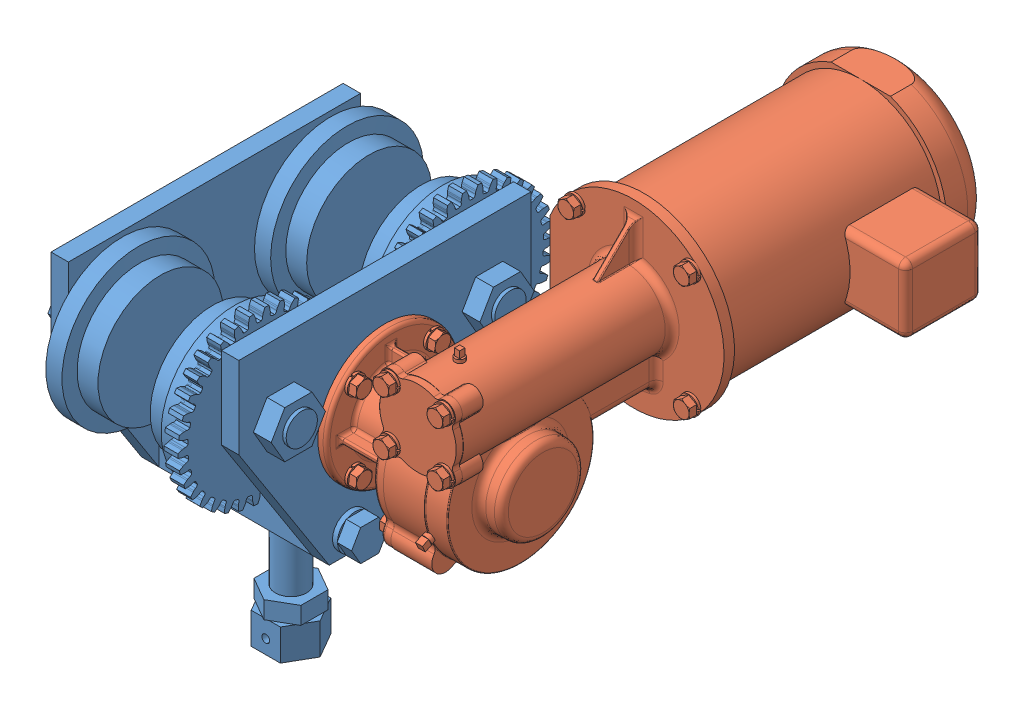
SolidWorks assembly M2632C-RH, configuration Default. Lengths in mm.
Overall size (418.5 387.47 540.72).
2 component instances, 2 part files, 3 mates.
Components (placement in the parent):
- Copy of M2632C-TROLLEY-SECTION^M2632C-RH-1: Copy of M2632C-TROLLEY-SECTION^M2632C-RH [3.25 PAT TRACK] at origin size (210.26 349.64 342.81) (virtual)
- Copy of SDT GEAR REDUCER TEMPLATE^M2632C-RH-1: Copy of SDT GEAR REDUCER TEMPLATE^M2632C-RH [Default] at (188.9125 104.394 0) size (229.23 225.42 451.54) (virtual)
Mates (geometry in assembly coordinates):
- Coincident1: coincident aligned: plane of Copy of M2632C-TROLLEY-SECTION^M2632C-RH-1 through (0 0 0) normal (0 0 1); plane of Copy of SDT GEAR REDUCER TEMPLATE^M2632C-RH-1 through (188.9125 104.394 0) normal (0 0 1)
- Coincident2: coincident aligned: plane of Copy of M2632C-TROLLEY-SECTION^M2632C-RH-1 through (0 104.394 0) normal (0 1 0); plane of Copy of SDT GEAR REDUCER TEMPLATE^M2632C-RH-1 through (188.9125 104.394 0) normal (0 1 0)
- Distance1: distance = 14.2875 mm aligned: plane of Copy of SDT GEAR REDUCER TEMPLATE^M2632C-RH-1 through (84.1375 104.394 0) normal (-1 0 0); plane of Copy of M2632C-TROLLEY-SECTION^M2632C-RH-1 through (69.85 203.2 -133.35) normal (-1 0 0)
